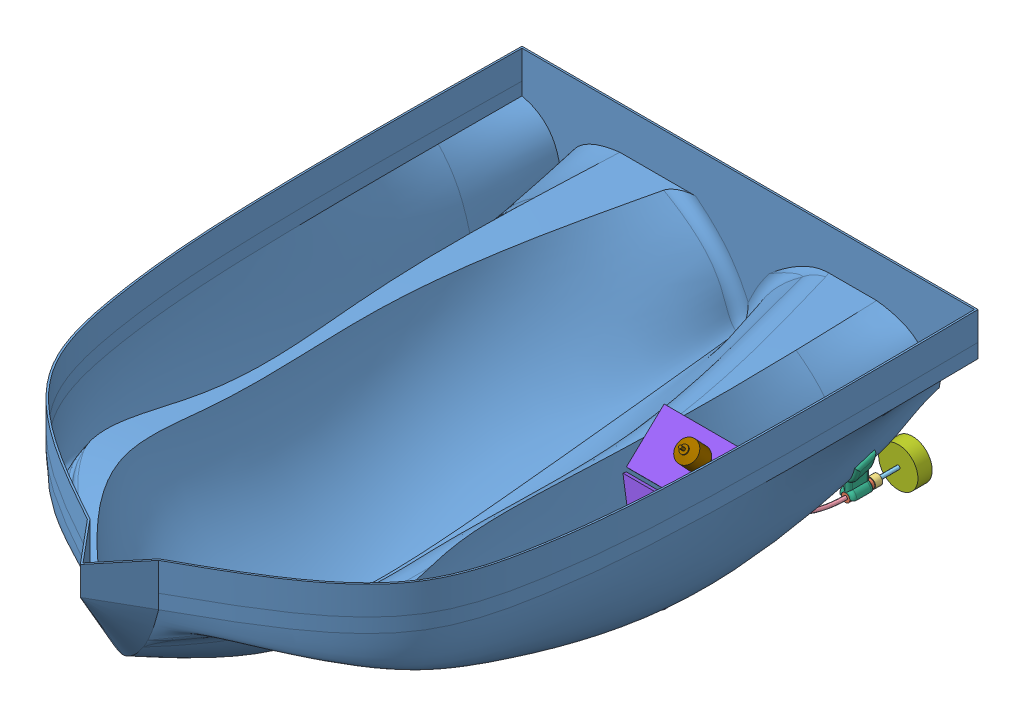
SolidWorks assembly Boat Propeller Assembly, configuration Default. Lengths in mm.
Overall size (903.87 305.3 1272.19).
11 component instances, 10 part files, 10 mates.
Components (placement in the parent):
- HullFormFINALed-1: HullFormFINALed [Default<As Machined>] at (494.9095 521.8965 873.0464) size (903.87 304.81 1272.19)
- boat hull measured-1: boat hull measured [Default] at (899.733 595.3265 421.0464) x (0 0 1) z (-1 0 0) size (229.1 149.1 174.75) (hidden)
- shaft assembly-1: shaft assembly [Default] at (814.2667 380.9103 536.3227) x (0 0 -1) z (1 0 0) size (347.45 164.02 40.93)
  - hull_tube_9_21_2016-1: hull_tube_9_21_2016 [Default] at (-44.6237 -26.3034 16.088) x (1 0 0) z (0 -0.279591 0.960119) size (55.88 15.24 15.24)
  - cap-1: cap [Default] at (-0.1737 -26.3034 16.088) size (12.7 17.78 17.78)
  - tube-1: tube [Default] at (-19.2237 -26.3034 16.088) size (253.47 157.75 6.35)
  - shaft prop coupling-1: shaft prop coupling [Default] at (-19.2237 -26.3034 16.088) x (1 0 0) z (0 -0.833873 0.551956) size (93.98 9.53 9.53)
  - Brace_boat_conform-1: Brace_boat_conform [Default<As Machined>] at (-336.7237 141.0036 -319.5521) x (0 0 1) z (-1 0 0) size (40.93 63.37 39.38)
- Octura 1270 Plastic standin-1: Octura 1270 Plastic standin [Default] at (830.3547 354.6069 461.5664) size (70 70 25.4)
- plywood frame-1: plywood frame [Default] at (827.1797 399.7202 640.275) x (0 0 -1) z (1 0 0) size (342.16 220.27 154.76)
- Motor_8_29_16-1: Motor_8_29_16 [Default] at (830.3547 553.1918 850.1822) x (0 0.728141 0.685427) z (-0.685427 -0.499088 0.530189) size (74.63 37.64 37.64)
Mates (geometry in assembly coordinates):
- Distance1: distance = 127 mm: plane of shaft assembly-1/Brace_boat_conform-1 through (906.0079 416.1712 542.8464) normal (0 0 -1); plane of HullFormFINALed-1 through (463.8157 425.5088 415.8464) normal (0 0 -1)
- Parallel3: parallel: line of HullFormFINALed-1 through (901.3095 598.0965 415.8464) axis (0 -1 0); line of shaft assembly-1/Brace_boat_conform-1 through (830.3547 389.3637 542.8464) axis (0 -1 0)
- Coincident9: coincident: face of HullFormFINALed-1; moEndPointRef_w of shaft assembly-1/Brace_boat_conform-1
- Coincident11: coincident aligned: circle of shaft assembly-1/shaft prop coupling-1; circle of Octura 1270 Plastic standin-1
- Tangent10: tangent anti-aligned: plane of plywood frame-1 through (833.5297 533.575 836.0765) normal (0 0.685427 -0.728141); cylinder of shaft assembly-1/tube-1 through (830.3547 414.533 719.6573) axis (0 0.728141 0.685427) radius 3.175
- Lock2: lock: unknown of HullFormFINALed-1; unknown of shaft assembly-1/Brace_boat_conform-1
- Tangent12: tangent anti-aligned: cylinder of shaft assembly-1/tube-1 through (830.3547 414.533 719.6573) axis (0 0.728141 0.685427) radius 3.175; plane of plywood frame-1 through (833.5297 533.575 836.0765) normal (0 0.685427 -0.728141)
- Parallel4: parallel aligned: line of HullFormFINALed-1 through (901.3095 598.0965 415.8464) axis (-1 0 0); line of plywood frame-1 through (890.5584 566.6834 810.1692) axis (-1 0 0)
- Coincident17: coincident anti-aligned: plane of plywood frame-1 through (827.1797 573.0344 803.4224) normal (0 0.728141 0.685427); plane of Motor_8_29_16-1 through (819.415 547.4334 830.6188) normal (0 -0.728141 -0.685427)
- Concentric1: concentric anti-aligned: cylinder of shaft assembly-1/tube-1 through (830.3547 414.533 719.6573) axis (0 0.728141 0.685427) radius 3.175; cylinder of Motor_8_29_16-1 through (830.3547 553.1918 850.1822) axis (0 -0.728141 -0.685427) radius 2.5019
